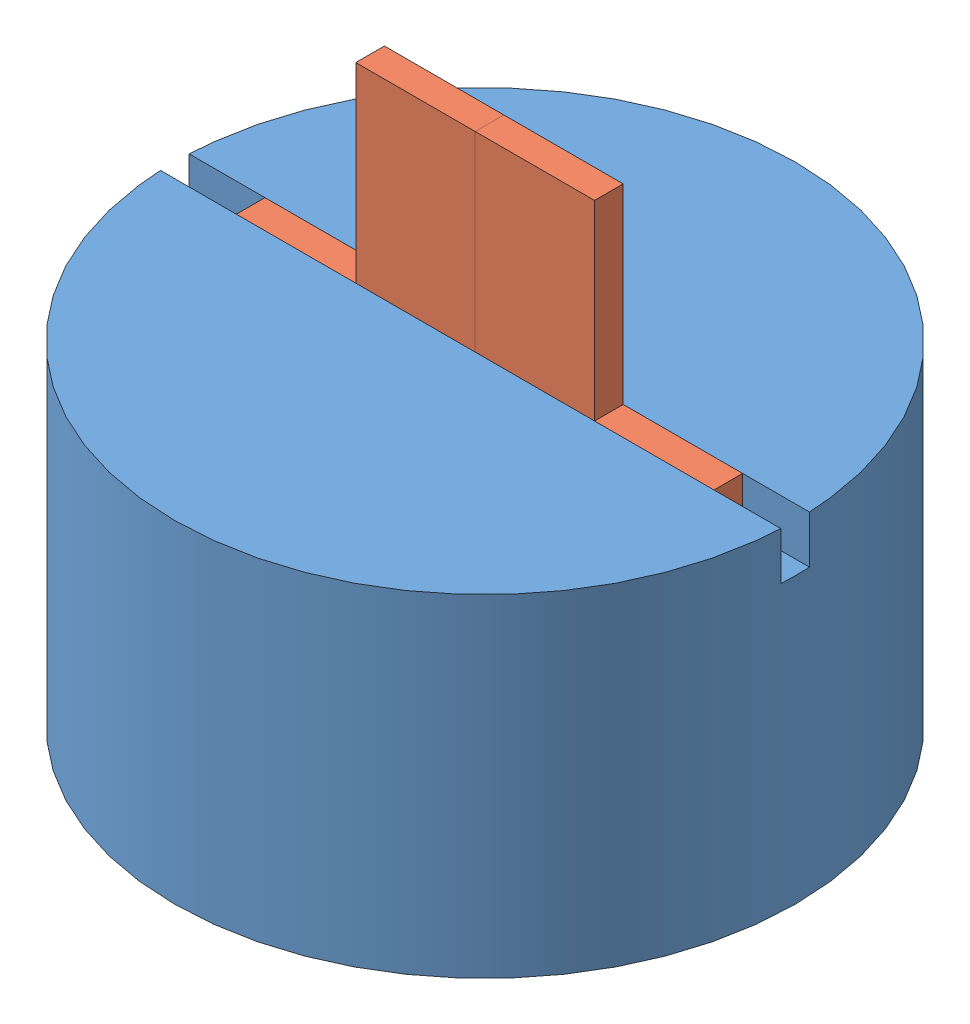
SolidWorks assembly gripper assem, configuration Default. Lengths in mm.
3 component instances, 2 part files, 7 mates.
Components (placement in the parent):
- gripper head-1: gripper head [Default] at (-38.0108 -7.62 13.4158) size (65 34.79 65)
- gripper jaw-1: gripper jaw [Default] at (-50.04 22.173 13.4158) size (25 25 3)
- gripper jaw-2: gripper jaw [Default] at (-25.04 22.173 13.4158) x (-1 0 0) z (0 0 -1) size (25 25 3)
Mates (geometry in assembly coordinates):
- Parallel1: parallel aligned: line of gripper head-1 through (-70.4762 27.173 14.9158) axis (0 -1 0); line of gripper jaw-1 through (-62.54 27.173 14.9158) axis (0 -1 0)
- Coincident1: coincident anti-aligned: plane of gripper head-1 through (-38.0108 22.173 13.4158) normal (0 1 0); plane of gripper jaw-1 through (-50.04 22.173 13.4158) normal (0 -1 0)
- Coincident2: coincident anti-aligned: plane of gripper head-1 through (-71.2009 22.173 14.9158) normal (0 0 -1); plane of gripper jaw-1 through (-50.04 47.173 14.9158) normal (0 0 1)
- Coincident3: coincident anti-aligned: plane of gripper head-1 through (-71.2009 22.173 14.9158) normal (0 0 -1); plane of gripper jaw-2 through (-25.04 47.173 14.9158) normal (0 0 1)
- LimitDistance1: limit distance = 12.54 mm: plane of assembly through (0 0 0) normal (1 0 0); plane of assembly; plane of gripper jaw-2 through (-12.54 27.173 13.4158) normal (1 0 0)
- Coincident5: coincident anti-aligned: plane of gripper head-1 through (-38.0108 22.173 13.4158) normal (0 1 0); plane of gripper jaw-2 through (-25.04 22.173 13.4158) normal (0 -1 0)
- LimitDistance2: limit distance = 37.54 mm: plane of assembly through (0 0 0) normal (1 0 0); plane of assembly; plane of gripper jaw-1 through (-37.54 47.173 13.4158) normal (1 0 0)
